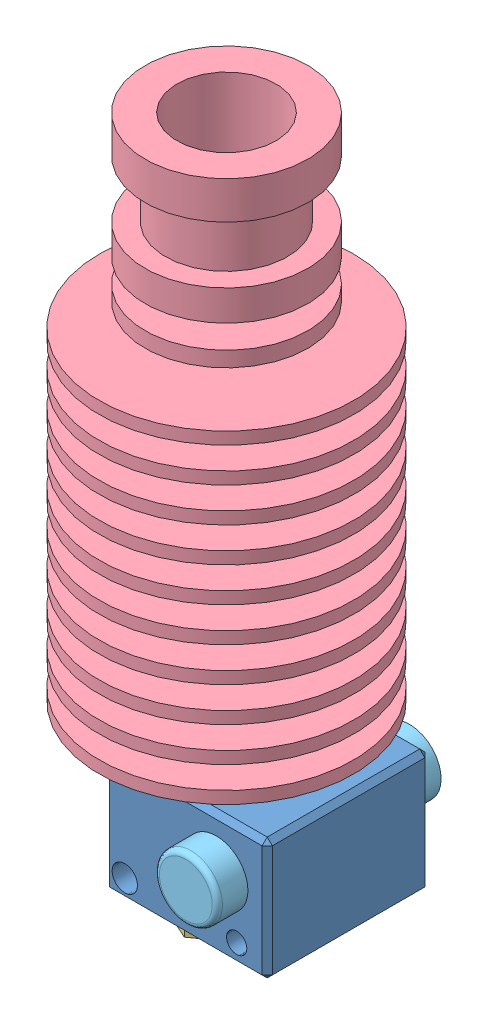
SolidWorks assembly E3D, configuration Default. Lengths in mm.
Overall size (28.79 69.7 37.75).
6 component instances, 6 part files, 10 mates.
Components (placement in the parent):
- E3D Heat Block-1: E3D Heat Block [Default] at origin size (16 12 16)
- E3D Heatbreak-1: E3D Heatbreak [Default] at (-4 19.55 0) x (-0.93266 0 -0.360757) z (-0.360757 0 0.93266) size (6 25.1 6)
- E3D Nozzle-1: E3D Nozzle [Default] at (-4 -3.5 0) x (-0.097107 0 -0.995274) z (0.995274 0 -0.097107) size (9.24 12.5 8)
- E3D Heatsink-1: E3D Heatsink [1.75 Bowden] at (-4 39.15 0) x (0.986263 0 -0.165183) z (0.165183 0 0.986263) size (25 50.1 25)
- cartridge heater-1: cartridge heater [Default] at (3 7 0) x (0 0 1) z (-0.150948 -0.988542 0) size (32 6.2 6.2)
- thermistor-1: thermistor [Default] at (-6 2 6.5) x (-0.997586 0.069447 0) z (-0.069447 -0.997586 0) size (2 13.25 2)
Mates (geometry in assembly coordinates):
- Concentric1: concentric anti-aligned: cylinder of E3D Heat Block-1 through (-4 12 0) axis (0 1 0) radius 2.5; cylinder of E3D Heatbreak-1 through (-4 7 0) axis (0 -1 0) radius 3
- Concentric2: concentric aligned: cylinder of E3D Heatbreak-1 through (-4 7 0) axis (0 -1 0) radius 3; cylinder of E3D Heatsink-1 through (-4 14.1 0) axis (0 -1 0) radius 3
- Coincident1: coincident aligned: plane of E3D Heatbreak-1 through (-5.3057 14.1 -0.5051) normal (0 -1 0); plane of E3D Heatsink-1 through (-1.0412 14.1 -0.4956) normal (0 -1 0)
- Concentric3: concentric anti-aligned: cylinder of E3D Heat Block-1 through (-4 12 0) axis (0 1 0) radius 2.5; cylinder of E3D Nozzle-1 through (-4 -5.5 0) axis (0 -1 0) radius 3
- Coincident2: coincident anti-aligned: plane of E3D Heatbreak-1 through (-4.9327 7 -0.3608) normal (0 -1 0); plane of E3D Nozzle-1 through (-4 7 0) normal (0 1 0)
- Coincident3: coincident aligned: plane of E3D Heat Block-1 through (0 12 0) normal (0 1 0); plane of E3D Heatbreak-1 through (-6.798 12 -1.0823) normal (0 1 0)
- Concentric601: concentric anti-aligned: cylinder of E3D Heat Block-1 through (3 7 -8) axis (0 0 1) radius 3.1; cylinder of cartridge heater-1 through (3 7 -11) axis (0 0 -1) radius 3.1
- Width1: width aligned: plane of cartridge heater-1 through (3.3925 9.5702 11) normal (0 0 1); plane of cartridge heater-1 through (3.4679 10.0645 -11) normal (0 0 -1); plane of E3D Heat Block-1 through (-8 12 8) normal (0 0 1); plane of E3D Heat Block-1 through (-8 12 -8) normal (0 0 -1)
- Concentric602: concentric aligned: cylinder of E3D Heat Block-1 through (-6 2 8) axis (0 0 1) radius 1.25; circle of thermistor-1
- Tangent1: tangent anti-aligned: plane of E3D Heat Block-1 through (-6 2 3.5) normal (0 0 1); sphere of thermistor-1
